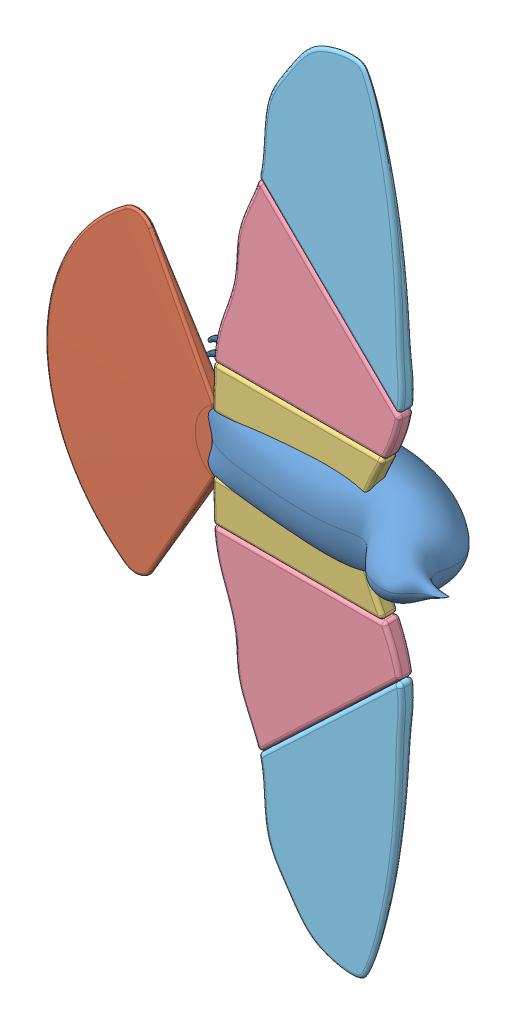
SolidWorks assembly Anatomically Accurate Pigeon, configuration Default. Lengths in mm.
Overall size (345.93 679.42 100.47).
32 component instances, 11 part files, 42 mates.
Components (placement in the parent):
- Torso-1: Torso [Default] at (-116.5382 -17.2811 -34.9858) x (0 1 0) z (1 0 0) size (77.03 98.72 217.79)
- Ghost Component-1: Ghost Component [Default] at (-321.5382 -17.2811 -53.5539) x (0 -1 0) z (-1 0 0) size (40 40 40) (hidden)
- Ghost Component-12: Ghost Component [Default] at (-321.5382 -17.2811 -53.5539) x (0 -1 0) z (-1 0 0) size (40 40 40) (hidden)
- Tail-1: Tail [Default] at (-321.5382 -17.2811 -53.5539) x (0 1 0) z (1 0 0) size (259.77 10.2 140.93)
- Ghost Component-2: Ghost Component [Default] at (-196.5382 5.0689 -53.5539) x (0 -1 0) z (-1 0 0) size (40 40 40) (hidden)
- Ghost Component-3: Ghost Component [Default] at (-196.5382 5.0689 -53.5539) x (0 -1 0) z (-1 0 0) size (40 40 40) (hidden)
- Upper Wing-1: Upper Wing [Default] at (-396.9178 -208.65 -53.5539) x (0 1 0) z (-1 0 0) size (35 20.3 138.35)
- Mid Wing-1: Mid Wing [Default] at (-396.9178 -208.65 -53.5539) x (0 1 0) z (-1 0 0) size (143.51 31.67 161.7)
- Ghost Component-4: Ghost Component [Default] at (-169.6039 75.0689 -53.5539) x (0 1 0) z (-1 0 0) size (40 40 40) (hidden)
- Ghost Component-5: Ghost Component [Default] at (-169.6039 75.0689 -53.5539) x (0 1 0) z (-1 0 0) size (40 40 40) (hidden)
- Hand Wing-1: Hand Wing [Default] at (-396.9178 -208.65 -53.5539) x (0 1 0) z (-1 0 0) size (259.11 41.69 150.62)
- Ghost Component-6: Ghost Component [Default] at (-196.5382 -39.6311 -53.5539) x (0 -1 0) z (-1 0 0) size (40 40 40) (hidden)
- Ghost Component-7: Ghost Component [Default] at (-196.5382 -39.6311 -53.5539) x (0 -1 0) z (-1 0 0) size (40 40 40) (hidden)
- Upper Wing-3: Upper Wing [Default] at (-396.9178 174.0879 -53.5538) x (0 -1 0) z (-1 0 0) size (35 20.3 138.35)
- Mid Wing-2: Mid Wing [Default] at (-396.9178 174.0879 -53.5538) x (0 -1 0) z (-1 0 0) size (143.51 31.67 161.7)
- Ghost Component-8: Ghost Component [Default] at (-169.6039 -109.6311 -53.5539) x (0 -1 0) z (-1 0 0) size (40 40 40) (hidden)
- Ghost Component-9: Ghost Component [Default] at (-169.6039 -109.6311 -53.5539) x (0 -1 0) z (-1 0 0) size (40 40 40) (hidden)
- Hand Wing-2: Hand Wing [Default] at (-396.9178 174.0879 -53.5539) x (0 -1 0) z (-1 0 0) size (259.11 41.69 150.62)
- Ghost Component-10: Ghost Component [Default] at (-246.5382 5.0689 -84.9858) x (0 -1 0) z (-1 0 0) size (40 40 40) (hidden)
- Leg Assembly-2: Leg Assembly [Default] at (-245.4048 5.0689 -87.6207) size (129.61 33.55 42.78)
  - Upper Leg-1: Upper Leg [Default] at (125.3079 0.7176 54.3308) x (0 1 0) z (1 0 0) size (33.55 41.36 43.09)
  - Mid Leg-1: Mid Leg [Default] at (125.3079 0.7176 54.3308) x (0 1 0) z (1 0 0) size (20 37.04 56.03)
  - Lower Leg-1: Lower Leg [Default] at (125.3079 0.7176 54.3308) x (0 1 0) z (1 0 0) size (13.26 19.61 34)
  - Thumb-1: Thumb [Default] at (125.1385 0.7176 54.542) x (0 1 0) z (1 0 0) size (6.01 15.63 23.37)
  - Finger-1: Finger [Default] at (125.1385 0.7176 54.542) x (0 1 0) z (1 0 0) size (29.58 16.17 35)
- Ghost Component-11: Ghost Component [Default] at (-246.5382 -39.6311 -84.9858) x (0 -1 0) z (-1 0 0) size (40 40 40) (hidden)
- Leg Assembly-3: Leg Assembly [Default] at (-245.4048 -39.6311 -87.6207) size (129.61 33.55 42.78)
  - Upper Leg-1: Upper Leg [Default] at (125.3079 0.7176 54.3308) x (0 1 0) z (1 0 0) size (33.55 41.36 43.09)
  - Mid Leg-1: Mid Leg [Default] at (125.3079 0.7176 54.3308) x (0 1 0) z (1 0 0) size (20 37.04 56.03)
  - Lower Leg-1: Lower Leg [Default] at (125.3079 0.7176 54.3308) x (0 1 0) z (1 0 0) size (13.26 19.61 34)
  - Thumb-1: Thumb [Default] at (125.1385 0.7176 54.542) x (0 1 0) z (1 0 0) size (6.01 15.63 23.37)
  - Finger-1: Finger [Default] at (125.1385 0.7176 54.542) x (0 1 0) z (1 0 0) size (29.58 16.17 35)
Mates (geometry in assembly coordinates):
- Coincident9: coincident anti-aligned: line of Ghost Component-1 through (-321.5382 -17.2811 -31.5539) axis (0 0 -1); line of Tail-1 through (-321.5382 -17.2811 -53.5539) axis (0 0 1)
- Coincident10: coincident aligned: plane of Ghost Component-1; plane of Tail-1
- Coincident12: coincident aligned: line of Torso-1 through (-345.2524 5.0689 -53.5539) axis (1 0 0); line of Ghost Component-2 through (-218.5382 5.0689 -53.5539) axis (1 0 0)
- Coincident13: coincident anti-aligned: plane of Torso-1 through (-196.5382 -17.2811 -34.9858) normal (1 0 0); plane of Ghost Component-2 through (-196.5382 5.0689 -53.5539) normal (-1 0 0)
- Coincident15: coincident aligned: line of Ghost Component-2 through (-196.5382 -16.9311 -53.5539) axis (0 1 0); line of Ghost Component-3 through (-196.5382 -16.9311 -53.5539) axis (0 1 0)
- Coincident17: coincident aligned: line of Ghost Component-3 through (-196.5382 5.0689 -31.5539) axis (0 0 -1); line of Upper Wing-1 through (-196.5382 5.0689 -53.5539) axis (0 0 -1)
- Coincident18: coincident anti-aligned: plane of Ghost Component-3; plane of Upper Wing-1
- Coincident19: coincident aligned: plane of Ghost Component-2; plane of Ghost Component-3
- Coincident21: coincident aligned: line of Upper Wing-1 through (-221.5182 40.0689 -53.5539) axis (0 0 -1); line of Mid Wing-1 through (-221.5182 40.0689 -53.5539) axis (0 0 -1)
- Coincident22: coincident aligned: plane of Upper Wing-1; plane of Mid Wing-1
- Coincident24: coincident anti-aligned: line of Mid Wing-1 through (-169.6039 75.0689 -53.5539) axis (-1 0 0); line of Ghost Component-4 through (-191.6039 75.0689 -53.5539) axis (1 0 0)
- Coincident25: coincident aligned: plane of Mid Wing-1 through (-169.6039 -208.65 -53.5539) normal (-1 0 0); plane of ? through (-169.6039 75.0689 -53.5539) normal (-1 0 0)
- Coincident27: coincident aligned: line of ? through (-169.6039 97.0689 -53.5539) axis (0 -1 0); line of Ghost Component-5 through (-169.6039 97.0689 -53.5539) axis (0 -1 0)
- Coincident29: coincident anti-aligned: line of ? through (-169.6039 75.0689 -75.5539) axis (0 0 1); line of Hand Wing-1 through (-169.6039 75.0689 -53.5539) axis (0 0 -1)
- Coincident30: coincident aligned: plane of ?; plane of ?
- Coincident31: coincident aligned: plane of ?; plane of ?
- Coincident33: coincident aligned: line of Torso-1 through (-345.2524 -39.6311 -53.5539) axis (1 0 0); line of Ghost Component-6 through (-218.5382 -39.6311 -53.5539) axis (1 0 0)
- Coincident34: coincident anti-aligned: plane of Torso-1 through (-196.5382 -17.2811 -34.9858) normal (1 0 0); plane of Ghost Component-6 through (-196.5382 -39.6311 -53.5539) normal (-1 0 0)
- Coincident37: coincident aligned: line of Ghost Component-6 through (-196.5382 -61.6311 -53.5539) axis (0 1 0); line of Ghost Component-7 through (-196.5382 -61.6311 -53.5539) axis (0 1 0)
- Coincident39: coincident anti-aligned: line of Ghost Component-7 through (-196.5382 -39.6311 -31.5539) axis (0 0 -1); line of Upper Wing-3 through (-196.5382 -39.6311 -53.5539) axis (0 0 1)
- Coincident40: coincident aligned: plane of Ghost Component-7; plane of ?
- Coincident41: coincident aligned: plane of Ghost Component-6; plane of Ghost Component-7
- Coincident43: coincident aligned: line of ? through (-221.5182 -74.6311 -53.5538) axis (0 0 1); line of Mid Wing-2 through (-221.5182 -74.6311 -53.5538) axis (0 0 1)
- Coincident44: coincident aligned: plane of ?; plane of ?
- Coincident46: coincident anti-aligned: line of ? through (-169.6039 -109.6311 -53.5539) axis (-1 0 0); line of Ghost Component-8 through (-191.6039 -109.6311 -53.5539) axis (1 0 0)
- Coincident47: coincident aligned: plane of ? through (-169.6039 174.0879 -53.5539) normal (-1 0 0); plane of Ghost Component-8 through (-169.6039 -109.6311 -53.5539) normal (-1 0 0)
- Coincident49: coincident aligned: line of Ghost Component-8 through (-169.6039 -131.6311 -53.5539) axis (0 1 0); line of Ghost Component-9 through (-169.6039 -131.6311 -53.5539) axis (0 1 0)
- Coincident51: coincident anti-aligned: line of Ghost Component-9 through (-169.6039 -109.6311 -31.5539) axis (0 0 -1); line of Hand Wing-2 through (-169.6039 -109.6311 -53.5539) axis (0 0 1)
- Coincident52: coincident aligned: plane of Ghost Component-9; plane of Hand Wing-2
- Coincident53: coincident aligned: plane of Ghost Component-8; plane of Ghost Component-9
- Coincident55: coincident aligned: line of Torso-1 through (-345.2524 5.0689 -84.9858) axis (1 0 0); line of Ghost Component-10 through (-268.5382 5.0689 -84.9858) axis (1 0 0)
- Coincident56: coincident anti-aligned: plane of Torso-1 through (-246.5382 -17.2811 -34.9858) normal (1 0 0); plane of Ghost Component-10 through (-246.5382 5.0689 -84.9858) normal (-1 0 0)
- Coincident57: coincident aligned: line of Ghost Component-10 through (-246.5382 -16.9311 -84.9858) axis (0 1 0); line of Leg Assembly-2/Upper Leg-1 through (-246.5382 5.7865 -84.9858) axis (0 1 0)
- Coincident58: coincident anti-aligned: plane of Ghost Component-10; plane of Leg Assembly-2 through (-245.4048 5.0689 -87.6207) normal (0 1 0)
- Coincident60: coincident anti-aligned: line of Torso-1 through (-105.6478 -39.6311 -84.9858) axis (-1 0 0); line of Ghost Component-11 through (-268.5382 -39.6311 -84.9858) axis (1 0 0)
- Coincident61: coincident anti-aligned: plane of Torso-1 through (-246.5382 -17.2811 -34.9858) normal (1 0 0); plane of Ghost Component-11 through (-246.5382 -39.6311 -84.9858) normal (-1 0 0)
- Coincident62: coincident aligned: line of Ghost Component-11 through (-246.5382 -61.6311 -84.9858) axis (0 1 0); line of ? through (-246.5382 -38.9135 -84.9858) axis (0 1 0)
- Coincident63: coincident anti-aligned: plane of Ghost Component-11; plane of Leg Assembly-3 through (-245.4048 -39.6311 -87.6207) normal (0 1 0)
- Coincident67: coincident aligned: line of Torso-1 through (-345.2159 -17.2811 -53.5539) axis (1 0 0); line of Ghost Component-12 through (-343.5382 -17.2811 -53.5539) axis (1 0 0)
- Coincident68: coincident anti-aligned: plane of Torso-1 through (-321.5382 -17.2811 -34.9858) normal (1 0 0); plane of ? through (-321.5382 -17.2811 -53.5539) normal (-1 0 0)
- Coincident69: coincident aligned: line of Ghost Component-1 through (-321.5382 -39.2811 -53.5539) axis (0 1 0); line of ? through (-321.5382 -39.2811 -53.5539) axis (0 1 0)
- Coincident71: coincident aligned: plane of Ghost Component-1; plane of ?
